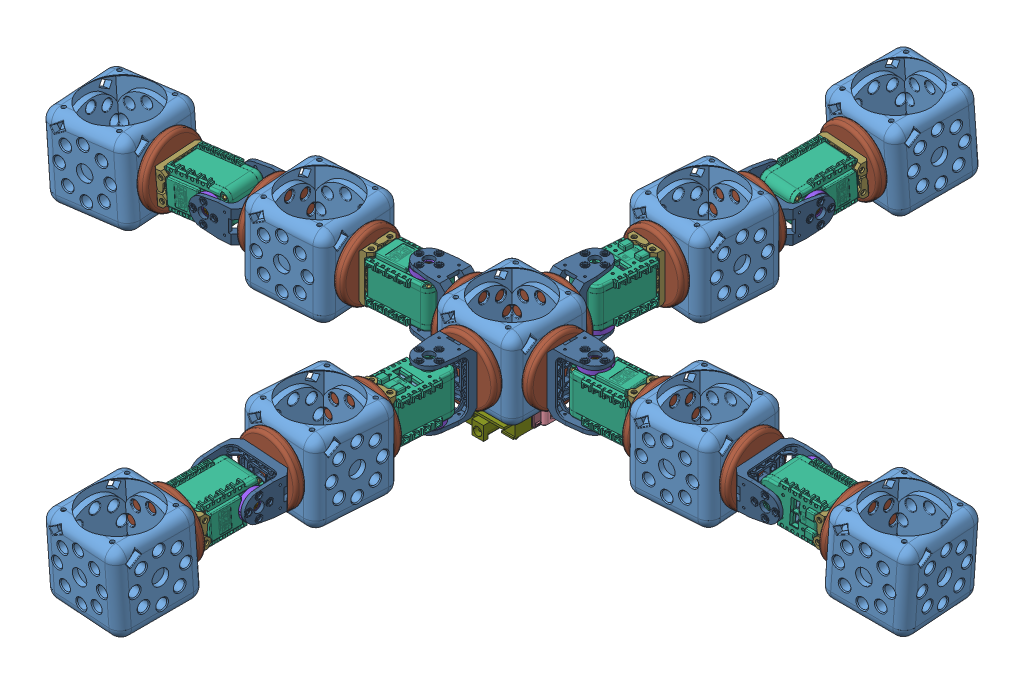
SolidWorks assembly spider_conf, configuration Default. Lengths in mm.
Overall size (666.21 89.51 668.44).
182 component instances, 22 part files, 53 mates.
Components (placement in the parent):
- Brick_with_component-1: Brick_with_component [Default] at (-89.0084 -14.2633 -1.1837) size (65.1 65 67.49)
  - brick_module-1: brick_module [Default] at (36.7874 45.3941 22.7481) size (65.1 65 67.49)
  - 3P Extension PCB-4: 3P Extension PCB [Default] at (16.3785 38.7483 76.0481) x (-1 0 0) z (0 0 -1) size (20 28.2 9.4)
- joint-1: joint [Default] at (-156.0952 -2.6333 299.1256) x (0.067269 0 0.997735) z (0 1 0) size (63.01 103.17 56.48)
  - Cover Screws^joint-8: Cover Screws^joint [Défaut] at (-252.3267 41.8937 41.7384) x (0 1 0) z (1 0 0) size (3.5 30.7 3.5) (virtual)
  - Insert M3^joint-2: Insert M3^joint [Défaut] at (-242.8267 33.3937 8.8384) x (-1 0 0) z (0 1 0) size (4.98 7 4.98) (virtual)
  - Cover Screws^joint-9: Cover Screws^joint [Défaut] at (-232.3267 0.3937 41.7384) x (0 1 0) z (1 0 0) size (3.5 30.7 3.5) (virtual)
  - 3 Pins Connector^joint-3: 3 Pins Connector^joint [Défaut] at (-237.7767 18.2037 17.4884) x (1 0 0) z (0 1 0) size (9.9 9.43 4.9) (virtual)
  - Cover Screws^joint-10: Cover Screws^joint [Défaut] at (-233.3267 41.8937 41.7384) x (0 1 0) z (1 0 0) size (3.5 30.7 3.5) (virtual)
  - 3 Pins Connector^joint-4: 3 Pins Connector^joint [Défaut] at (-247.7767 18.2037 17.4884) x (1 0 0) z (0 1 0) size (9.9 9.43 4.9) (virtual)
  - Body^joint-2: Body^joint [Défaut] at (-242.8267 33.3937 27.2384) size (32 50.04 38.37) (virtual)
  - Horn Assembly^joint-2: Horn Assembly^joint [Default] at (-242.8267 33.3937 48.1184) x (-1 0 0) z (0 0 1) size (22 22 9.6) (virtual)
    - Wheel Gear^Horn Assembly_joint-1: Wheel Gear^Horn Assembly_joint [Défaut] at (0 0 -22.94) size (6.5 6.5 5.51) (virtual)
    - Horn^Horn Assembly_joint-1: Horn^Horn Assembly_joint [Défaut] at (0 0 -1.84) x (0 -1 0) z (0 0 1) size (22 22 6.7) (virtual)
    - BHS M2x8^Horn Assembly_joint-1: BHS M2x8^Horn Assembly_joint [Défaut] at (0 0 -1.39) x (1 0 0) z (0 -1 0) size (5.5 9.6 5.5) (virtual)
  - Cover Screws^joint-11: Cover Screws^joint [Défaut] at (-253.3267 0.3937 41.7384) x (0 1 0) z (1 0 0) size (3.5 30.7 3.5) (virtual)
  - FP04-F2.stp-3: FP04-F2.stp [Default] at (-243.3649 33.4118 27.1184) x (0 0 1) z (0.067269 0.997735 0) size (48.8 25 37)
  - servo_module-8: servo_module [Default] at (-242.8267 -16.1063 27.2384) size (56.36 17 56.36)
  - servo_module-9: servo_module [Default] at (-241.0777 67.3348 27.1184) x (-0.997735 0.067269 0) z (0 0 1) size (56.36 17 56.36)
  - FP04-F3.stp-2: FP04-F3.stp [Default] at (-242.8267 -8.1063 27.2384) size (25 9 38)
- joint-2: joint [Default] at (10.8352 -2.6333 -190.9968) x (-0.067269 0 -0.997735) z (0 1 0) size (63.01 103.17 56.48)
  - Cover Screws^joint-8: Cover Screws^joint [Défaut] at (-252.3267 41.8937 41.7384) x (0 1 0) z (1 0 0) size (3.5 30.7 3.5) (virtual)
  - Insert M3^joint-2: Insert M3^joint [Défaut] at (-242.8267 33.3937 8.8384) x (-1 0 0) z (0 1 0) size (4.98 7 4.98) (virtual)
  - Cover Screws^joint-9: Cover Screws^joint [Défaut] at (-232.3267 0.3937 41.7384) x (0 1 0) z (1 0 0) size (3.5 30.7 3.5) (virtual)
  - 3 Pins Connector^joint-3: 3 Pins Connector^joint [Défaut] at (-237.7767 18.2037 17.4884) x (1 0 0) z (0 1 0) size (9.9 9.43 4.9) (virtual)
  - Cover Screws^joint-10: Cover Screws^joint [Défaut] at (-233.3267 41.8937 41.7384) x (0 1 0) z (1 0 0) size (3.5 30.7 3.5) (virtual)
  - 3 Pins Connector^joint-4: 3 Pins Connector^joint [Défaut] at (-247.7767 18.2037 17.4884) x (1 0 0) z (0 1 0) size (9.9 9.43 4.9) (virtual)
  - Body^joint-2: Body^joint [Défaut] at (-242.8267 33.3937 27.2384) size (32 50.04 38.37) (virtual)
  - Horn Assembly^joint-2: Horn Assembly^joint [Default] at (-242.8267 33.3937 48.1184) x (-1 0 0) z (0 0 1) size (22 22 9.6) (virtual)
    - Wheel Gear^Horn Assembly_joint-1: Wheel Gear^Horn Assembly_joint [Défaut] at (0 0 -22.94) size (6.5 6.5 5.51) (virtual)
    - Horn^Horn Assembly_joint-1: Horn^Horn Assembly_joint [Défaut] at (0 0 -1.84) x (0 -1 0) z (0 0 1) size (22 22 6.7) (virtual)
    - BHS M2x8^Horn Assembly_joint-1: BHS M2x8^Horn Assembly_joint [Défaut] at (0 0 -1.39) x (1 0 0) z (0 -1 0) size (5.5 9.6 5.5) (virtual)
  - Cover Screws^joint-11: Cover Screws^joint [Défaut] at (-253.3267 0.3937 41.7384) x (0 1 0) z (1 0 0) size (3.5 30.7 3.5) (virtual)
  - FP04-F2.stp-3: FP04-F2.stp [Default] at (-243.3649 33.4118 27.1184) x (0 0 1) z (0.067269 0.997735 0) size (48.8 25 37)
  - servo_module-8: servo_module [Default] at (-242.8267 -16.1063 27.2384) size (56.36 17 56.36)
  - servo_module-9: servo_module [Default] at (-241.0777 67.3348 27.1184) x (-0.997735 0.067269 0) z (0 0 1) size (56.36 17 56.36)
  - FP04-F3.stp-2: FP04-F3.stp [Default] at (-242.8267 -8.1063 27.2384) size (25 9 38)
- joint-3: joint [Default] at (172.4312 51.6034 -29.4008) x (0.997735 0 0.067269) z (0 -1 0) size (63.01 103.17 56.48)
  - Cover Screws^joint-8: Cover Screws^joint [Défaut] at (-252.3267 41.8937 41.7384) x (0 1 0) z (1 0 0) size (3.5 30.7 3.5) (virtual)
  - Insert M3^joint-2: Insert M3^joint [Défaut] at (-242.8267 33.3937 8.8384) x (-1 0 0) z (0 1 0) size (4.98 7 4.98) (virtual)
  - Cover Screws^joint-9: Cover Screws^joint [Défaut] at (-232.3267 0.3937 41.7384) x (0 1 0) z (1 0 0) size (3.5 30.7 3.5) (virtual)
  - 3 Pins Connector^joint-3: 3 Pins Connector^joint [Défaut] at (-237.7767 18.2037 17.4884) x (1 0 0) z (0 1 0) size (9.9 9.43 4.9) (virtual)
  - Cover Screws^joint-10: Cover Screws^joint [Défaut] at (-233.3267 41.8937 41.7384) x (0 1 0) z (1 0 0) size (3.5 30.7 3.5) (virtual)
  - 3 Pins Connector^joint-4: 3 Pins Connector^joint [Défaut] at (-247.7767 18.2037 17.4884) x (1 0 0) z (0 1 0) size (9.9 9.43 4.9) (virtual)
  - Body^joint-2: Body^joint [Défaut] at (-242.8267 33.3937 27.2384) size (32 50.04 38.37) (virtual)
  - Horn Assembly^joint-2: Horn Assembly^joint [Default] at (-242.8267 33.3937 48.1184) x (-1 0 0) z (0 0 1) size (22 22 9.6) (virtual)
    - Wheel Gear^Horn Assembly_joint-1: Wheel Gear^Horn Assembly_joint [Défaut] at (0 0 -22.94) size (6.5 6.5 5.51) (virtual)
    - Horn^Horn Assembly_joint-1: Horn^Horn Assembly_joint [Défaut] at (0 0 -1.84) x (0 -1 0) z (0 0 1) size (22 22 6.7) (virtual)
    - BHS M2x8^Horn Assembly_joint-1: BHS M2x8^Horn Assembly_joint [Défaut] at (0 0 -1.39) x (1 0 0) z (0 -1 0) size (5.5 9.6 5.5) (virtual)
  - Cover Screws^joint-11: Cover Screws^joint [Défaut] at (-253.3267 0.3937 41.7384) x (0 1 0) z (1 0 0) size (3.5 30.7 3.5) (virtual)
  - FP04-F2.stp-3: FP04-F2.stp [Default] at (-243.3649 33.4118 27.1184) x (0 0 1) z (0.067269 0.997735 0) size (48.8 25 37)
  - servo_module-8: servo_module [Default] at (-242.8267 -16.1063 27.2384) size (56.36 17 56.36)
  - servo_module-9: servo_module [Default] at (-241.0777 67.3348 27.1184) x (-0.997735 0.067269 0) z (0 0 1) size (56.36 17 56.36)
  - FP04-F3.stp-2: FP04-F3.stp [Default] at (-242.8267 -8.1063 27.2384) size (25 9 38)
- joint-4: joint [Default] at (-317.6912 51.6034 137.5296) x (-0.997735 0 -0.067269) z (0 -1 0) size (63.01 103.17 56.48)
  - Cover Screws^joint-8: Cover Screws^joint [Défaut] at (-252.3267 41.8937 41.7384) x (0 1 0) z (1 0 0) size (3.5 30.7 3.5) (virtual)
  - Insert M3^joint-2: Insert M3^joint [Défaut] at (-242.8267 33.3937 8.8384) x (-1 0 0) z (0 1 0) size (4.98 7 4.98) (virtual)
  - Cover Screws^joint-9: Cover Screws^joint [Défaut] at (-232.3267 0.3937 41.7384) x (0 1 0) z (1 0 0) size (3.5 30.7 3.5) (virtual)
  - 3 Pins Connector^joint-3: 3 Pins Connector^joint [Défaut] at (-237.7767 18.2037 17.4884) x (1 0 0) z (0 1 0) size (9.9 9.43 4.9) (virtual)
  - Cover Screws^joint-10: Cover Screws^joint [Défaut] at (-233.3267 41.8937 41.7384) x (0 1 0) z (1 0 0) size (3.5 30.7 3.5) (virtual)
  - 3 Pins Connector^joint-4: 3 Pins Connector^joint [Défaut] at (-247.7767 18.2037 17.4884) x (1 0 0) z (0 1 0) size (9.9 9.43 4.9) (virtual)
  - Body^joint-2: Body^joint [Défaut] at (-242.8267 33.3937 27.2384) size (32 50.04 38.37) (virtual)
  - Horn Assembly^joint-2: Horn Assembly^joint [Default] at (-242.8267 33.3937 48.1184) x (-1 0 0) z (0 0 1) size (22 22 9.6) (virtual)
    - Wheel Gear^Horn Assembly_joint-1: Wheel Gear^Horn Assembly_joint [Défaut] at (0 0 -22.94) size (6.5 6.5 5.51) (virtual)
    - Horn^Horn Assembly_joint-1: Horn^Horn Assembly_joint [Défaut] at (0 0 -1.84) x (0 -1 0) z (0 0 1) size (22 22 6.7) (virtual)
    - BHS M2x8^Horn Assembly_joint-1: BHS M2x8^Horn Assembly_joint [Défaut] at (0 0 -1.39) x (1 0 0) z (0 -1 0) size (5.5 9.6 5.5) (virtual)
  - Cover Screws^joint-11: Cover Screws^joint [Défaut] at (-253.3267 0.3937 41.7384) x (0 1 0) z (1 0 0) size (3.5 30.7 3.5) (virtual)
  - FP04-F2.stp-3: FP04-F2.stp [Default] at (-243.3649 33.4118 27.1184) x (0 0 1) z (0.067269 0.997735 0) size (48.8 25 37)
  - servo_module-8: servo_module [Default] at (-242.8267 -16.1063 27.2384) size (56.36 17 56.36)
  - servo_module-9: servo_module [Default] at (-241.0777 67.3348 27.1184) x (-0.997735 0.067269 0) z (0 0 1) size (56.36 17 56.36)
  - FP04-F3.stp-2: FP04-F3.stp [Default] at (-242.8267 -8.1063 27.2384) size (25 9 38)
- Brick_with_component-2: Brick_with_component [Default] at (-79.2007 -14.3833 -150.4564) x (0.997735 0 0.067269) z (-0.067269 0 0.997735) size (65.1 65 67.49)
  - brick_module-1: brick_module [Default] at (36.7874 45.3941 22.7481) size (65.1 65 67.49)
  - 3P Extension PCB-4: 3P Extension PCB [Default] at (16.3785 38.7483 76.0481) x (-1 0 0) z (0 0 -1) size (20 28.2 9.4)
- Brick_with_component-3: Brick_with_component [Default] at (55.6083 -14.1433 -6.011) x (0.997735 0 -0.067269) z (0.067269 0 0.997735) size (65.1 65 67.49)
  - brick_module-1: brick_module [Default] at (36.7874 45.3941 22.7481) size (65.1 65 67.49)
  - 3P Extension PCB-4: 3P Extension PCB [Default] at (16.3785 38.7483 76.0481) x (-1 0 0) z (0 0 -1) size (20 28.2 9.4)
- Brick_with_component-5: Brick_with_component [Default] at (-240.984 -14.1433 6.0974) x (0.997735 0 -0.067269) z (0.067269 0 0.997735) size (65.1 65 67.49)
  - brick_module-1: brick_module [Default] at (36.7874 45.3941 22.7481) size (65.1 65 67.49)
  - 3P Extension PCB-4: 3P Extension PCB [Default] at (16.3785 38.7483 76.0481) x (-1 0 0) z (0 0 -1) size (20 28.2 9.4)
- Brick_with_component-6: Brick_with_component [Default] at (-91.3091 -14.3833 146.1359) x (0.997735 0 0.067269) z (-0.067269 0 0.997735) size (65.1 65 67.49)
  - brick_module-1: brick_module [Default] at (36.7874 45.3941 22.7481) size (65.1 65 67.49)
  - 3P Extension PCB-4: 3P Extension PCB [Default] at (16.3785 38.7483 76.0481) x (-1 0 0) z (0 0 -1) size (20 28.2 9.4)
- joint-5: joint [Default] at (160.7665 -220.4561 69.4526) x (-0.067117 -0.997735 0.004525) z (-0.067269 0 -0.997735) size (63.01 103.17 56.48)
  - Cover Screws^joint-8: Cover Screws^joint [Défaut] at (-252.3267 41.8937 41.7384) x (0 1 0) z (1 0 0) size (3.5 30.7 3.5) (virtual)
  - Insert M3^joint-2: Insert M3^joint [Défaut] at (-242.8267 33.3937 8.8384) x (-1 0 0) z (0 1 0) size (4.98 7 4.98) (virtual)
  - Cover Screws^joint-9: Cover Screws^joint [Défaut] at (-232.3267 0.3937 41.7384) x (0 1 0) z (1 0 0) size (3.5 30.7 3.5) (virtual)
  - 3 Pins Connector^joint-3: 3 Pins Connector^joint [Défaut] at (-237.7767 18.2037 17.4884) x (1 0 0) z (0 1 0) size (9.9 9.43 4.9) (virtual)
  - Cover Screws^joint-10: Cover Screws^joint [Défaut] at (-233.3267 41.8937 41.7384) x (0 1 0) z (1 0 0) size (3.5 30.7 3.5) (virtual)
  - 3 Pins Connector^joint-4: 3 Pins Connector^joint [Défaut] at (-247.7767 18.2037 17.4884) x (1 0 0) z (0 1 0) size (9.9 9.43 4.9) (virtual)
  - Body^joint-2: Body^joint [Défaut] at (-242.8267 33.3937 27.2384) size (32 50.04 38.37) (virtual)
  - Horn Assembly^joint-2: Horn Assembly^joint [Default] at (-242.8267 33.3937 48.1184) x (-1 0 0) z (0 0 1) size (22 22 9.6) (virtual)
    - Wheel Gear^Horn Assembly_joint-1: Wheel Gear^Horn Assembly_joint [Défaut] at (0 0 -22.94) size (6.5 6.5 5.51) (virtual)
    - Horn^Horn Assembly_joint-1: Horn^Horn Assembly_joint [Défaut] at (0 0 -1.84) x (0 -1 0) z (0 0 1) size (22 22 6.7) (virtual)
    - BHS M2x8^Horn Assembly_joint-1: BHS M2x8^Horn Assembly_joint [Défaut] at (0 0 -1.39) x (1 0 0) z (0 -1 0) size (5.5 9.6 5.5) (virtual)
  - Cover Screws^joint-11: Cover Screws^joint [Défaut] at (-253.3267 0.3937 41.7384) x (0 1 0) z (1 0 0) size (3.5 30.7 3.5) (virtual)
  - FP04-F2.stp-3: FP04-F2.stp [Default] at (-243.3649 33.4118 27.1184) x (0 0 1) z (0.067269 0.997735 0) size (48.8 25 37)
  - servo_module-8: servo_module [Default] at (-242.8267 -16.1063 27.2384) size (56.36 17 56.36)
  - servo_module-9: servo_module [Default] at (-241.0777 67.3348 27.1184) x (-0.997735 0.067269 0) z (0 0 1) size (56.36 17 56.36)
  - FP04-F3.stp-2: FP04-F3.stp [Default] at (-242.8267 -8.1063 27.2384) size (25 9 38)
- joint-6: joint [Default] at (-111.3558 -220.6961 283.8125) x (0.004525 -0.997735 -0.067117) z (0.997735 0 0.067269) size (63.01 103.17 56.48)
  - Cover Screws^joint-8: Cover Screws^joint [Défaut] at (-252.3267 41.8937 41.7384) x (0 1 0) z (1 0 0) size (3.5 30.7 3.5) (virtual)
  - Insert M3^joint-2: Insert M3^joint [Défaut] at (-242.8267 33.3937 8.8384) x (-1 0 0) z (0 1 0) size (4.98 7 4.98) (virtual)
  - Cover Screws^joint-9: Cover Screws^joint [Défaut] at (-232.3267 0.3937 41.7384) x (0 1 0) z (1 0 0) size (3.5 30.7 3.5) (virtual)
  - 3 Pins Connector^joint-3: 3 Pins Connector^joint [Défaut] at (-237.7767 18.2037 17.4884) x (1 0 0) z (0 1 0) size (9.9 9.43 4.9) (virtual)
  - Cover Screws^joint-10: Cover Screws^joint [Défaut] at (-233.3267 41.8937 41.7384) x (0 1 0) z (1 0 0) size (3.5 30.7 3.5) (virtual)
  - 3 Pins Connector^joint-4: 3 Pins Connector^joint [Défaut] at (-247.7767 18.2037 17.4884) x (1 0 0) z (0 1 0) size (9.9 9.43 4.9) (virtual)
  - Body^joint-2: Body^joint [Défaut] at (-242.8267 33.3937 27.2384) size (32 50.04 38.37) (virtual)
  - Horn Assembly^joint-2: Horn Assembly^joint [Default] at (-242.8267 33.3937 48.1184) x (-1 0 0) z (0 0 1) size (22 22 9.6) (virtual)
    - Wheel Gear^Horn Assembly_joint-1: Wheel Gear^Horn Assembly_joint [Défaut] at (0 0 -22.94) size (6.5 6.5 5.51) (virtual)
    - Horn^Horn Assembly_joint-1: Horn^Horn Assembly_joint [Défaut] at (0 0 -1.84) x (0 -1 0) z (0 0 1) size (22 22 6.7) (virtual)
    - BHS M2x8^Horn Assembly_joint-1: BHS M2x8^Horn Assembly_joint [Défaut] at (0 0 -1.39) x (1 0 0) z (0 -1 0) size (5.5 9.6 5.5) (virtual)
  - Cover Screws^joint-11: Cover Screws^joint [Défaut] at (-253.3267 0.3937 41.7384) x (0 1 0) z (1 0 0) size (3.5 30.7 3.5) (virtual)
  - FP04-F2.stp-3: FP04-F2.stp [Default] at (-243.3649 33.4118 27.1184) x (0 0 1) z (0.067269 0.997735 0) size (48.8 25 37)
  - servo_module-8: servo_module [Default] at (-242.8267 -16.1063 27.2384) size (56.36 17 56.36)
  - servo_module-9: servo_module [Default] at (-241.0777 67.3348 27.1184) x (-0.997735 0.067269 0) z (0 0 1) size (56.36 17 56.36)
  - FP04-F3.stp-2: FP04-F3.stp [Default] at (-242.8267 -8.1063 27.2384) size (25 9 38)
- joint-9: joint [Default] at (-88.0181 269.4263 -179.3321) x (-0.004525 0.997735 0.067117) z (0.997735 0 0.067269) size (63.01 103.17 56.48)
  - Cover Screws^joint-8: Cover Screws^joint [Défaut] at (-252.3267 41.8937 41.7384) x (0 1 0) z (1 0 0) size (3.5 30.7 3.5) (virtual)
  - Insert M3^joint-2: Insert M3^joint [Défaut] at (-242.8267 33.3937 8.8384) x (-1 0 0) z (0 1 0) size (4.98 7 4.98) (virtual)
  - Cover Screws^joint-9: Cover Screws^joint [Défaut] at (-232.3267 0.3937 41.7384) x (0 1 0) z (1 0 0) size (3.5 30.7 3.5) (virtual)
  - 3 Pins Connector^joint-3: 3 Pins Connector^joint [Défaut] at (-237.7767 18.2037 17.4884) x (1 0 0) z (0 1 0) size (9.9 9.43 4.9) (virtual)
  - Cover Screws^joint-10: Cover Screws^joint [Défaut] at (-233.3267 41.8937 41.7384) x (0 1 0) z (1 0 0) size (3.5 30.7 3.5) (virtual)
  - 3 Pins Connector^joint-4: 3 Pins Connector^joint [Défaut] at (-247.7767 18.2037 17.4884) x (1 0 0) z (0 1 0) size (9.9 9.43 4.9) (virtual)
  - Body^joint-2: Body^joint [Défaut] at (-242.8267 33.3937 27.2384) size (32 50.04 38.37) (virtual)
  - Horn Assembly^joint-2: Horn Assembly^joint [Default] at (-242.8267 33.3937 48.1184) x (-1 0 0) z (0 0 1) size (22 22 9.6) (virtual)
    - Wheel Gear^Horn Assembly_joint-1: Wheel Gear^Horn Assembly_joint [Défaut] at (0 0 -22.94) size (6.5 6.5 5.51) (virtual)
    - Horn^Horn Assembly_joint-1: Horn^Horn Assembly_joint [Défaut] at (0 0 -1.84) x (0 -1 0) z (0 0 1) size (22 22 6.7) (virtual)
    - BHS M2x8^Horn Assembly_joint-1: BHS M2x8^Horn Assembly_joint [Défaut] at (0 0 -1.39) x (1 0 0) z (0 -1 0) size (5.5 9.6 5.5) (virtual)
  - Cover Screws^joint-11: Cover Screws^joint [Défaut] at (-253.3267 0.3937 41.7384) x (0 1 0) z (1 0 0) size (3.5 30.7 3.5) (virtual)
  - FP04-F2.stp-3: FP04-F2.stp [Default] at (-243.3649 33.4118 27.1184) x (0 0 1) z (0.067269 0.997735 0) size (48.8 25 37)
  - servo_module-8: servo_module [Default] at (-242.8267 -16.1063 27.2384) size (56.36 17 56.36)
  - servo_module-9: servo_module [Default] at (-241.0777 67.3348 27.1184) x (-0.997735 0.067269 0) z (0 0 1) size (56.36 17 56.36)
  - FP04-F3.stp-2: FP04-F3.stp [Default] at (-242.8267 -8.1063 27.2384) size (25 9 38)
- joint-10: joint [Default] at (-306.0265 -220.4561 38.6763) x (0.067117 -0.997735 -0.004525) z (0.067269 0 0.997735) size (63.01 103.17 56.48)
  - Cover Screws^joint-8: Cover Screws^joint [Défaut] at (-252.3267 41.8937 41.7384) x (0 1 0) z (1 0 0) size (3.5 30.7 3.5) (virtual)
  - Insert M3^joint-2: Insert M3^joint [Défaut] at (-242.8267 33.3937 8.8384) x (-1 0 0) z (0 1 0) size (4.98 7 4.98) (virtual)
  - Cover Screws^joint-9: Cover Screws^joint [Défaut] at (-232.3267 0.3937 41.7384) x (0 1 0) z (1 0 0) size (3.5 30.7 3.5) (virtual)
  - 3 Pins Connector^joint-3: 3 Pins Connector^joint [Défaut] at (-237.7767 18.2037 17.4884) x (1 0 0) z (0 1 0) size (9.9 9.43 4.9) (virtual)
  - Cover Screws^joint-10: Cover Screws^joint [Défaut] at (-233.3267 41.8937 41.7384) x (0 1 0) z (1 0 0) size (3.5 30.7 3.5) (virtual)
  - 3 Pins Connector^joint-4: 3 Pins Connector^joint [Défaut] at (-247.7767 18.2037 17.4884) x (1 0 0) z (0 1 0) size (9.9 9.43 4.9) (virtual)
  - Body^joint-2: Body^joint [Défaut] at (-242.8267 33.3937 27.2384) size (32 50.04 38.37) (virtual)
  - Horn Assembly^joint-2: Horn Assembly^joint [Default] at (-242.8267 33.3937 48.1184) x (-1 0 0) z (0 0 1) size (22 22 9.6) (virtual)
    - Wheel Gear^Horn Assembly_joint-1: Wheel Gear^Horn Assembly_joint [Défaut] at (0 0 -22.94) size (6.5 6.5 5.51) (virtual)
    - Horn^Horn Assembly_joint-1: Horn^Horn Assembly_joint [Défaut] at (0 0 -1.84) x (0 -1 0) z (0 0 1) size (22 22 6.7) (virtual)
    - BHS M2x8^Horn Assembly_joint-1: BHS M2x8^Horn Assembly_joint [Défaut] at (0 0 -1.39) x (1 0 0) z (0 -1 0) size (5.5 9.6 5.5) (virtual)
  - Cover Screws^joint-11: Cover Screws^joint [Défaut] at (-253.3267 0.3937 41.7384) x (0 1 0) z (1 0 0) size (3.5 30.7 3.5) (virtual)
  - FP04-F2.stp-3: FP04-F2.stp [Default] at (-243.3649 33.4118 27.1184) x (0 0 1) z (0.067269 0.997735 0) size (48.8 25 37)
  - servo_module-8: servo_module [Default] at (-242.8267 -16.1063 27.2384) size (56.36 17 56.36)
  - servo_module-9: servo_module [Default] at (-241.0777 67.3348 27.1184) x (-0.997735 0.067269 0) z (0 0 1) size (56.36 17 56.36)
  - FP04-F3.stp-2: FP04-F3.stp [Default] at (-242.8267 -8.1063 27.2384) size (25 9 38)
- Brick_with_component-7: Brick_with_component [Default] at (-386.2984 -21.2115 16.0151) x (0.995475 0.067269 -0.067117) z (0.067269 0 0.997735) size (65.1 65 67.49)
  - brick_module-1: brick_module [Default] at (36.7874 45.3941 22.7481) size (65.1 65 67.49)
  - 3P Extension PCB-4: 3P Extension PCB [Default] at (16.3785 38.7483 76.0481) x (-1 0 0) z (0 0 -1) size (20 28.2 9.4)
- Brick_with_component-8: Brick_with_component [Default] at (-68.9383 -4.5248 -300.8844) x (0.997735 0 0.067269) z (-0.067117 -0.067269 0.995475) size (65.1 65 67.49)
  - brick_module-1: brick_module [Default] at (36.7874 45.3941 22.7481) size (65.1 65 67.49)
  - 3P Extension PCB-4: 3P Extension PCB [Default] at (16.3785 38.7483 76.0481) x (-1 0 0) z (0 0 -1) size (20 28.2 9.4)
- Brick_with_component-9: Brick_with_component [Default] at (201.0023 -18.8829 -15.978) x (0.995475 -0.067269 -0.067117) z (0.067117 -0.002263 0.997743) size (65.1 65 67.49)
  - brick_module-1: brick_module [Default] at (36.7874 45.3941 22.7481) size (65.1 65 67.49)
  - 3P Extension PCB-4: 3P Extension PCB [Default] at (16.3785 38.7483 76.0481) x (-1 0 0) z (0 0 -1) size (20 28.2 9.4)
- Brick_with_component-10: Brick_with_component [Default] at (-100.9981 -16.6332 291.6284) x (0.997735 0 0.067269) z (-0.067117 -0.067269 0.995475) size (65.1 65 67.49)
  - brick_module-1: brick_module [Default] at (36.7874 45.3941 22.7481) size (65.1 65 67.49)
  - 3P Extension PCB-4: 3P Extension PCB [Default] at (16.3785 38.7483 76.0481) x (-1 0 0) z (0 0 -1) size (20 28.2 9.4)
- U2D2 Power Hub Board.stp-1: U2D2 Power Hub Board.stp [Default] at (-158.33 -14.7339 236.5543) x (0.00146 0 -0.999999) z (0 -1 0) size (62.03 48.04 19.13)
  - ROBOTIS_U2D2_Power_Hub_Board.stp-1: ROBOTIS_U2D2_Power_Hub_Board.stp [Default] at origin size (62.03 48 18.87)
    - 39281023.stp.stp-1: 39281023.stp.stp [Default] at (181.1 102.95 -5.2189) x (1 0 0) z (0 -1 0) size (6.2 16.3 11)
      - 39281023.prt.stp-1: 39281023.prt.stp [Default] at (-0.4 0 0) size (6.2 16.3 11)
    - JST-B4B-EH-A.PRT.1.stp-1: JST-B4B-EH-A.PRT.1.stp [Default] at (169.49 68.4835 -5.0189) x (0 -1 0) z (-1 0 0) size (12.5 9.2 3.8)
    - JST-B4B-EH-A.PRT.1.stp-2: JST-B4B-EH-A.PRT.1.stp [Default] at (175.49 68.4835 -5.0189) x (0 -1 0) z (-1 0 0) size (12.5 9.2 3.8)
    - JST-B3B-EH-A.PRT.1.stp-1: JST-B3B-EH-A.PRT.1.stp [Default] at (169.49 80.4335 -5.0189) x (0 -1 0) z (-1 0 0) size (10 9.2 3.8)
    - JST-B3B-EH-A.PRT.1.stp-2: JST-B3B-EH-A.PRT.1.stp [Default] at (175.49 80.4335 -5.0189) x (0 -1 0) z (-1 0 0) size (10 9.2 3.8)
    - JST-B4B-EH-A.PRT.1.stp-3: JST-B4B-EH-A.PRT.1.stp [Default] at (181.39 68.4835 -5.0189) x (0 -1 0) z (-1 0 0) size (12.5 9.2 3.8)
    - Board.stp-1: Board.stp [Default] at origin size (62.03 48 18.87)
    - JST-B3B-EH-A.PRT.1.stp-3: JST-B3B-EH-A.PRT.1.stp [Default] at (181.39 80.4335 -5.0189) x (0 -1 0) z (-1 0 0) size (10 9.2 3.8)
  - ROBOTIS_U2D2.stp-1: ROBOTIS_U2D2.stp [Default] at origin size (18 48 14.6)
    - U2D2.ASM.stp-1: U2D2.ASM.stp [Default] at (232.4354 97.6021 -24.4036) x (0 -1 0) z (-1 0 0) size (48 14.6 18)
      - JST-B3B-EH-A.PRT.stp-1: JST-B3B-EH-A.PRT.stp [Default] at (26.1036 27.3847 36.9478) size (10 9.2 3.8)
      - JST-B4B-EH-A.PRT.stp-1: JST-B4B-EH-A.PRT.stp [Default] at (24.8536 27.3847 33.0978) size (12.5 9.2 3.8)
      - JST-B4B-PH-K-S.PRT.stp-1: JST-B4B-PH-K-S.PRT.stp [Default] at (36.0036 27.3847 45.6478) x (-1 0 0) z (0 0 -1) size (9.9 9.4 4.5)
      - MICRO_USB_2_0_CONNECTOR__AB_REC.PRT.stp-1: MICRO_USB_2_0_CONNECTOR__AB_REC.PRT.stp [Default] at (-9.6963 29.5461 38.7478) size (5.91 3.39 8.65)
      - PCB_U2D2.PRT.stp-1: PCB_U2D2.PRT.stp [Default] at (0 27.3847 0) x (-1 0 0) z (0 -1 0) size (45 15 1)
      - U2D2_CASING.PRT.stp-1: U2D2_CASING.PRT.stp [Default] at (-11.7964 19.3847 47.7478) size (48 14.6 18)
Mates (geometry in assembly coordinates):
- Concentric2: concentric aligned: cylinder of Brick_with_component-1/brick_module-1 through (-95.63 43.7851 54.0644) axis (-1 0 0) radius 4.1; cylinder of joint-1/servo_module-9 through (-96.13 43.7851 54.0644) axis (-1 0 0) radius 3.8
- Coincident3: coincident anti-aligned: plane of Brick_with_component-1/brick_module-1 through (-105.13 -8.0149 86.5644) normal (-1 0 0); plane of joint-1/servo_module-9 through (-105.13 24.4851 54.0644) normal (1 0 0)
- Concentric3: concentric aligned: line of Brick_with_component-1/brick_module-1 through (-95.63 5.1851 54.0644) axis (-1 0 0); cylinder of joint-1/servo_module-9 through (-96.13 5.1851 54.0644) axis (-1 0 0) radius 3.8
- Concentric4: concentric aligned: cylinder of Brick_with_component-1/brick_module-1 through (-49.63 43.7851 54.0644) axis (1 0 0) radius 4.1; cylinder of joint-2/servo_module-9 through (-49.13 43.7851 54.0644) axis (1 0 0) radius 3.8
- Concentric5: concentric aligned: cylinder of Brick_with_component-1/brick_module-1 through (-50.13 24.4851 73.3644) axis (1 0 0) radius 4.1; cylinder of joint-2/servo_module-9 through (-49.13 24.4851 73.3644) axis (1 0 0) radius 3.8
- Coincident4: coincident anti-aligned: plane of Brick_with_component-1/brick_module-1 through (-40.13 -8.0149 86.5644) normal (1 0 0); plane of joint-2/servo_module-9 through (-40.13 24.4851 54.0644) normal (-1 0 0)
- Concentric6: concentric anti-aligned: cylinder of Brick_with_component-1/brick_module-1 through (-72.63 5.1851 21.5644) axis (0 0 1) radius 4.1; cylinder of joint-3/servo_module-9 through (-72.63 5.1851 30.5644) axis (0 0 -1) radius 3.8
- Concentric7: concentric anti-aligned: cylinder of Brick_with_component-1/brick_module-1 through (-72.63 43.7851 21.5644) axis (0 0 1) radius 4.1; cylinder of joint-3/servo_module-9 through (-72.63 43.7851 30.5644) axis (0 0 -1) radius 3.8
- Coincident5: coincident anti-aligned: plane of Brick_with_component-1/brick_module-1 through (-52.221 31.1308 21.5644) normal (0 0 -1); plane of joint-3/servo_module-9 through (-72.63 24.4851 21.5644) normal (0 0 1)
- Concentric8: concentric aligned: cylinder of Brick_with_component-1/brick_module-1 through (-72.63 5.1851 76.5644) axis (0 0 1) radius 4.1; cylinder of joint-4/servo_module-9 through (-72.63 5.1851 77.5644) axis (0 0 1) radius 3.8
- Concentric9: concentric aligned: cylinder of Brick_with_component-1/brick_module-1 through (-72.63 43.7851 76.5644) axis (0 0 1) radius 4.1; cylinder of joint-4/servo_module-9 through (-72.63 43.7851 77.5644) axis (0 0 1) radius 3.8
- Coincident6: coincident anti-aligned: plane of Brick_with_component-1/brick_module-1 through (-52.221 31.1308 86.5644) normal (0 0 1); plane of joint-4/servo_module-9 through (-72.63 24.4851 86.5644) normal (0 0 -1)
- Concentric10: concentric aligned: cylinder of joint-3/servo_module-8 through (-68.1566 5.0651 -70.7849) axis (-0.067269 0 0.997735) radius 3.8; cylinder of Brick_with_component-2/brick_module-1 through (-68.0893 5.0651 -71.7827) axis (-0.067269 0 0.997735) radius 4.1
- Concentric11: concentric aligned: cylinder of joint-3/servo_module-8 through (-68.1566 43.6651 -70.7849) axis (-0.067269 0 0.997735) radius 3.8; cylinder of Brick_with_component-2/brick_module-1 through (-68.0893 43.6651 -71.7827) axis (-0.067269 0 0.997735) radius 4.1
- Coincident7: coincident anti-aligned: plane of joint-3/servo_module-8 through (-68.762 24.3651 -61.8053) normal (0.067269 0 -0.997735); plane of Brick_with_component-2/brick_module-1 through (-48.3993 31.0108 -60.4324) normal (-0.067269 0 0.997735)
- Coincident10: coincident anti-aligned: plane of joint-2/servo_module-8 through (43.2398 24.6051 50.1965) normal (0.997735 0 -0.067269); plane of Brick_with_component-3/brick_module-1 through (45.426 -7.8949 82.6229) normal (-0.997735 0 0.067269)
- Concentric16: concentric aligned: cylinder of joint-2/servo_module-8 through (52.2194 5.3051 49.5911) axis (-0.997735 0 0.067269) radius 3.8; cylinder of Brick_with_component-3/brick_module-1 through (53.2171 5.3051 49.5238) axis (-0.997735 0 0.067269) radius 4.1
- Concentric18: concentric aligned: cylinder of joint-2/servo_module-8 through (52.2194 43.9051 49.5911) axis (-0.997735 0 0.067269) radius 3.8; cylinder of Brick_with_component-3/brick_module-1 through (52.7183 43.9051 49.5574) axis (-0.997735 0 0.067269) radius 4.1
- Concentric19: concentric aligned: cylinder of joint-1/servo_module-8 through (-197.4794 5.3051 58.5378) axis (0.997735 0 -0.067269) radius 3.8; cylinder of Brick_with_component-5/brick_module-1 through (-198.4771 5.3051 58.6051) axis (0.997735 0 -0.067269) radius 4.1
- Concentric20: concentric aligned: cylinder of joint-1/servo_module-8 through (-197.4794 43.9051 58.5378) axis (0.997735 0 -0.067269) radius 3.8; cylinder of Brick_with_component-5/brick_module-1 through (-197.9782 43.9051 58.5715) axis (0.997735 0 -0.067269) radius 4.1
- Coincident11: coincident anti-aligned: plane of joint-1/servo_module-8 through (-188.4997 24.6051 57.9324) normal (-0.997735 0 0.067269); plane of Brick_with_component-5/brick_module-1 through (-186.3135 -7.8949 90.3588) normal (0.997735 0 -0.067269)
- Concentric21: concentric anti-aligned: cylinder of joint-4/servo_module-8 through (-77.1034 5.0651 178.9138) axis (0.067269 0 -0.997735) radius 3.8; cylinder of Brick_with_component-6/brick_module-1 through (-76.4979 5.0651 169.9342) axis (-0.067269 0 0.997735) radius 4.1
- Concentric22: concentric anti-aligned: cylinder of joint-4/servo_module-8 through (-77.1034 43.6651 178.9138) axis (0.067269 0 -0.997735) radius 3.8; cylinder of Brick_with_component-6/brick_module-1 through (-76.4979 43.6651 169.9342) axis (-0.067269 0 0.997735) radius 4.1
- Coincident12: coincident anti-aligned: plane of joint-4/servo_module-8 through (-76.4979 24.3651 169.9342) normal (-0.067269 0 0.997735); plane of Brick_with_component-6/brick_module-1 through (-56.1352 31.0108 171.3071) normal (0.067269 0 -0.997735)
- Concentric25: concentric aligned: cylinder of Brick_with_component-3/brick_module-1 through (98.1152 5.3051 46.4967) axis (0.997735 0 -0.067269) radius 4.1; cylinder of joint-5/servo_module-9 through (99.1129 5.3051 46.4294) axis (0.997735 0 -0.067269) radius 3.8
- Concentric26: concentric aligned: cylinder of Brick_with_component-3/brick_module-1 through (98.6141 43.9051 46.4631) axis (0.997735 0 -0.067269) radius 4.1; cylinder of joint-5/servo_module-9 through (99.1129 43.9051 46.4294) axis (0.997735 0 -0.067269) radius 3.8
- Coincident13: coincident anti-aligned: plane of Brick_with_component-3/brick_module-1 through (110.2788 -7.8949 78.2504) normal (0.997735 0 -0.067269); plane of joint-5/servo_module-9 through (108.0925 24.6051 45.824) normal (-0.997735 0 0.067269)
- Concentric29: concentric aligned: cylinder of Brick_with_component-6/brick_module-1 through (-80.1977 5.0651 224.8096) axis (-0.067269 0 0.997735) radius 4.1; cylinder of joint-6/servo_module-9 through (-80.265 5.0651 225.8074) axis (-0.067269 0 0.997735) radius 3.8
- Concentric30: concentric aligned: cylinder of Brick_with_component-6/brick_module-1 through (-80.1977 43.6651 224.8096) axis (-0.067269 0 0.997735) radius 4.1; cylinder of joint-6/servo_module-9 through (-80.265 43.6651 225.8074) axis (-0.067269 0 0.997735) radius 3.8
- Coincident17: coincident anti-aligned: plane of Brick_with_component-6/brick_module-1 through (-60.5077 31.0108 236.1599) normal (-0.067269 0 0.997735); plane of joint-6/servo_module-9 through (-80.8704 24.3651 234.787) normal (0.067269 0 -0.997735)
- Concentric33: concentric anti-aligned: cylinder of Brick_with_component-2/brick_module-1 through (-64.3895 5.0651 -126.6581) axis (-0.067269 0 0.997735) radius 4.1; cylinder of joint-9/servo_module-9 through (-64.995 5.0651 -117.6785) axis (0.067269 0 -0.997735) radius 3.8
- Concentric34: concentric anti-aligned: cylinder of Brick_with_component-2/brick_module-1 through (-64.3895 43.6651 -126.6581) axis (-0.067269 0 0.997735) radius 4.1; cylinder of joint-9/servo_module-9 through (-64.995 43.6651 -117.6785) axis (0.067269 0 -0.997735) radius 3.8
- Coincident19: coincident anti-aligned: plane of Brick_with_component-2/brick_module-1 through (-44.0268 31.0108 -125.2852) normal (0.067269 0 -0.997735); plane of joint-9/servo_module-9 through (-64.3895 24.3651 -126.6581) normal (-0.067269 0 0.997735)
- Concentric35: concentric aligned: cylinder of Brick_with_component-5/brick_module-1 through (-243.3752 5.3051 61.6322) axis (-0.997735 0 0.067269) radius 4.1; cylinder of joint-10/servo_module-9 through (-244.3729 5.3051 61.6995) axis (-0.997735 0 0.067269) radius 3.8
- Concentric36: concentric aligned: cylinder of Brick_with_component-5/brick_module-1 through (-243.874 43.9051 61.6658) axis (-0.997735 0 0.067269) radius 4.1; cylinder of joint-10/servo_module-9 through (-244.3729 43.9051 61.6995) axis (-0.997735 0 0.067269) radius 3.8
- Coincident20: coincident anti-aligned: plane of Brick_with_component-5/brick_module-1 through (-251.1663 -7.8949 94.7313) normal (-0.997735 0 0.067269); plane of joint-10/servo_module-9 through (-253.3525 24.6051 62.3049) normal (0.997735 0 -0.067269)
- Concentric37: concentric aligned: cylinder of joint-10/servo_module-8 through (-344.1893 0.8754 68.5495) axis (0.995475 0.067269 -0.067117) radius 3.8; cylinder of Brick_with_component-7/brick_module-1 through (-345.1847 0.8081 68.6166) axis (0.995475 0.067269 -0.067117) radius 4.1
- Concentric38: concentric aligned: cylinder of joint-10/servo_module-8 through (-346.78 39.388 68.7242) axis (0.995475 0.067269 -0.067117) radius 3.8; cylinder of Brick_with_component-7/brick_module-1 through (-347.2777 39.3543 68.7578) axis (0.995475 0.067269 -0.067117) radius 4.1
- Coincident21: coincident anti-aligned: plane of joint-10/servo_module-8 through (-336.5253 20.7371 68.0328) normal (-0.995475 -0.067269 0.067117); plane of Brick_with_component-7/brick_module-1 through (-332.1578 -11.6893 100.3121) normal (0.995475 0.067269 -0.067117)
- Concentric42: concentric anti-aligned: cylinder of joint-6/servo_module-8 through (-86.8756 0.6354 325.6399) axis (0.067117 0.067269 -0.995475) radius 3.8; cylinder of Brick_with_component-10/brick_module-1 through (-86.2716 1.2408 316.6806) axis (-0.067117 -0.067269 0.995475) radius 4.1
- Concentric43: concentric anti-aligned: cylinder of joint-6/servo_module-8 through (-87.0503 39.148 328.2306) axis (0.067117 0.067269 -0.995475) radius 3.8; cylinder of Brick_with_component-10/brick_module-1 through (-86.4462 39.7534 319.2713) axis (-0.067117 -0.067269 0.995475) radius 4.1
- Coincident23: coincident anti-aligned: plane of joint-6/servo_module-8 through (-86.3589 20.4971 317.976) normal (-0.067117 -0.067269 0.995475); plane of Brick_with_component-10/brick_module-1 through (-66.0262 27.1278 319.7949) normal (0.067117 0.067269 -0.995475)
- Concentric47: concentric aligned: cylinder of joint-5/servo_module-8 through (198.9293 0.8754 39.5794) axis (-0.995475 0.067269 0.067117) radius 3.8; cylinder of Brick_with_component-9/brick_module-1 through (199.9248 0.8081 39.5122) axis (-0.995475 0.067269 0.067117) radius 4.1
- Parallel5: parallel aligned: cylinder of joint-5/servo_module-8 through (200.2226 33.7479 25.814) axis (-0.995475 0.067269 0.067117) radius 3.8; cylinder of Brick_with_component-9/brick_module-1 through (202.0236 39.3542 39.4585) axis (-0.995475 0.067269 0.067117) radius 4.1
- Coincident26: coincident anti-aligned: plane of joint-5/servo_module-8 through (191.2654 20.7371 40.0961) normal (0.995475 -0.067269 -0.067117); plane of Brick_with_component-9/brick_module-1 through (191.2634 -11.7628 72.6399) normal (-0.995475 0.067269 0.067117)
- Concentric49: concentric aligned: cylinder of joint-9/servo_module-8 through (-57.9702 9.5822 -220.0855) axis (-0.067117 -0.067269 0.995475) radius 3.8; cylinder of Brick_with_component-8/brick_module-1 through (-57.9031 9.6494 -221.081) axis (-0.067117 -0.067269 0.995475) radius 4.1
- Concentric50: concentric aligned: cylinder of joint-9/servo_module-8 through (-58.1449 48.0947 -217.4948) axis (-0.067117 -0.067269 0.995475) radius 3.8; cylinder of Brick_with_component-8/brick_module-1 through (-58.0778 48.162 -218.4903) axis (-0.067117 -0.067269 0.995475) radius 4.1
- Coincident27: coincident anti-aligned: plane of joint-9/servo_module-8 through (-58.6616 28.233 -209.8309) normal (0.067117 0.067269 -0.995475); plane of Brick_with_component-8/brick_module-1 through (-38.3289 34.8637 -208.012) normal (-0.067117 -0.067269 0.995475)
- Concentric51: concentric aligned: cylinder of Brick_with_component-1/brick_module-1 through (-51.63 -6.0149 78.0644) axis (0 -1 0) radius 1.65; cylinder of U2D2 Power Hub Board.stp-1/ROBOTIS_U2D2_Power_Hub_Board.stp-1/Board.stp-1 through (-51.63 -8.6147 78.0644) axis (0 -1 0) radius 2
- Parallel6: parallel aligned: cylinder of Brick_with_component-1/brick_module-1 through (-93.63 -6.0149 30.0644) axis (0 -1 0) radius 1.65; cylinder of U2D2 Power Hub Board.stp-1/ROBOTIS_U2D2_Power_Hub_Board.stp-1/Board.stp-1 through (-93.6298 -8.6147 29.9631) axis (0 -1 0) radius 2
- Coincident28: coincident anti-aligned: circle of Brick_with_component-1/brick_module-1; plane of U2D2 Power Hub Board.stp-1/ROBOTIS_U2D2_Power_Hub_Board.stp-1/Board.stp-1 through (-72.6115 -8.0149 41.4393) normal (0 1 0)
- Parallel7: parallel aligned: cylinder of Brick_with_component-1/brick_module-1 through (-93.63 -6.0149 30.0644) axis (0 -1 0) radius 1.65; cylinder of U2D2 Power Hub Board.stp-1/ROBOTIS_U2D2_Power_Hub_Board.stp-1/Board.stp-1 through (-93.6298 -8.6147 29.9631) axis (0 -1 0) radius 2
- Parallel8: parallel aligned: cylinder of Brick_with_component-1/brick_module-1 through (-93.63 -6.0149 78.0644) axis (0 -1 0) radius 1.65; cylinder of U2D2 Power Hub Board.stp-1/ROBOTIS_U2D2_Power_Hub_Board.stp-1/Board.stp-1 through (-93.6999 -8.6147 78.003) axis (0 -1 0) radius 2
